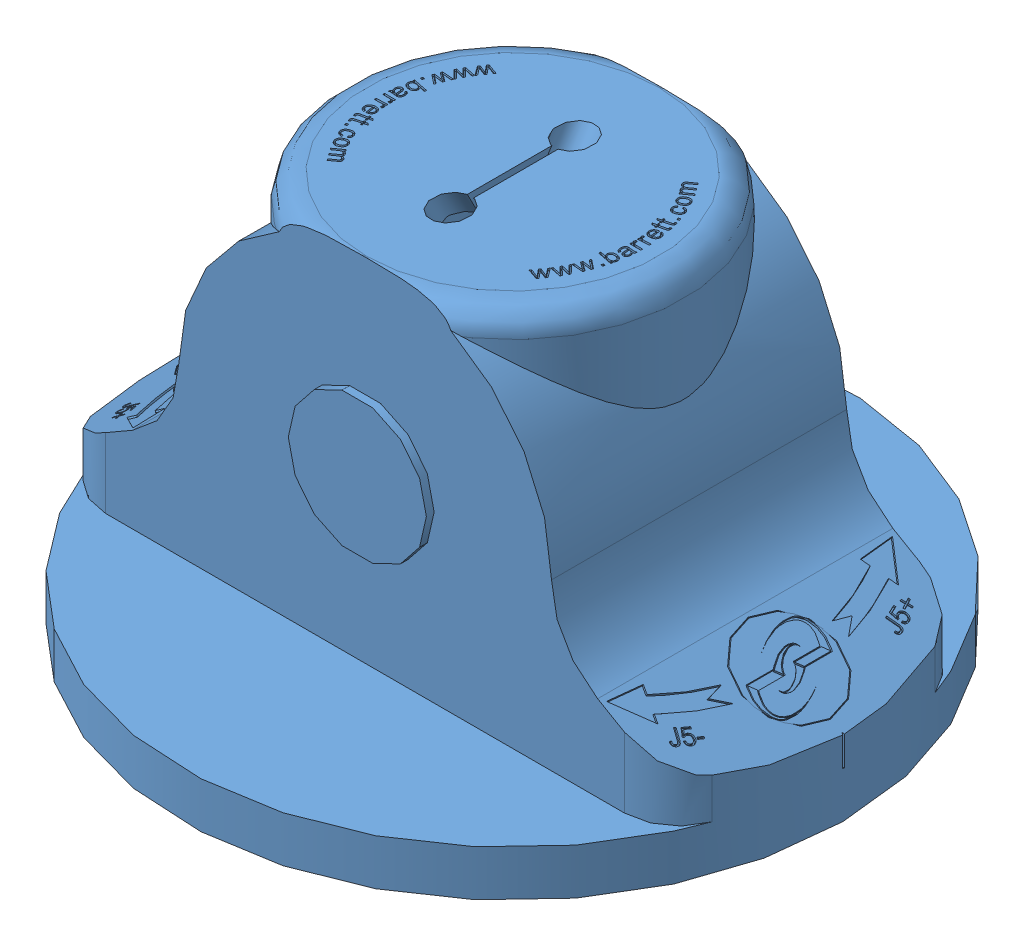
SolidWorks assembly B3310, configuration Default. Lengths in mm.
Overall size (85 52.32 85).
6 component instances, 3 part files, 6 mates.
Components (placement in the parent):
- B3308-2: B3308 [Default] x (0 0 -1) z (1 0 0) size (85 52.32 85)
- B1995-1: B1995 [5] x (1 0 0) z (0 0 -1) size (239.39 157.62 264.32) (suppressed, hidden)
  - B1998-1: B1998 [X5] x (0 0 -1) z (1 0 0)
  - B1998-2: B1998 [Y5] x (0 0 1) z (0 1 0)
  - B1998-3: B1998 [Z5] at origin
  - B1999-2: B1999 [100] at (0 0 197.2124) x (0 0 -1) z (0.268665 -0.963234 0)
Mates (geometry in assembly coordinates):
- Coincident1: coincident anti-aligned: plane of B1995-1; plane of assembly
- Coincident2: coincident aligned: plane of B1995-1; plane of assembly through (0 0 0) normal (1 0 0)
- Coincident3: coincident anti-aligned: plane of B1995-1; plane of assembly through (0 0 0) normal (0 1 0)
- Coincident4: coincident aligned: plane of B3308-2; plane of assembly
- Coincident5: coincident anti-aligned: plane of B3308-2; plane of assembly
- Coincident6: coincident aligned: plane of B3308-2; plane of assembly
